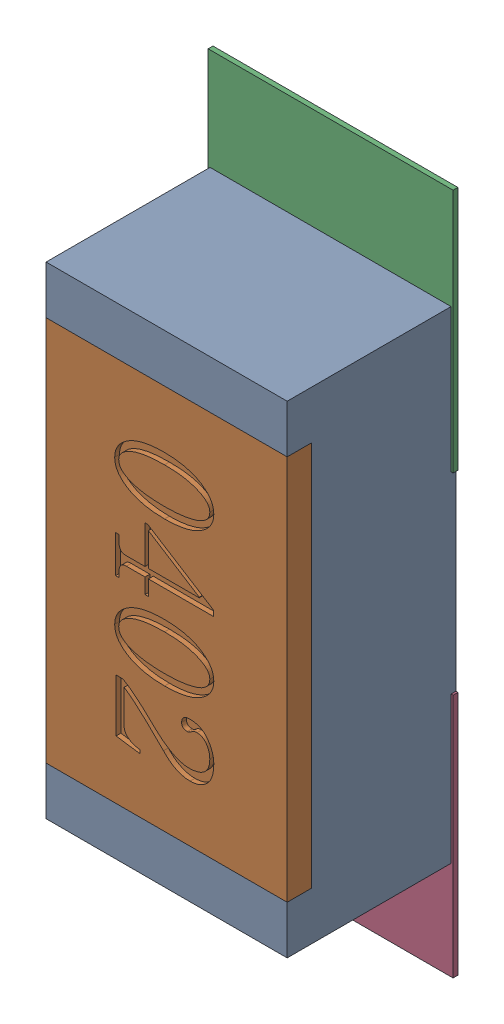
SolidWorks assembly R20, configuration Défaut. Lengths in mm.
Overall size (0.51 1.42 0.35).
5 component instances, 2 part files, 0 mates.
Components (placement in the parent):
- R0402-1: R0402 [Défaut] at (32.5373 -8.4908 0) x (0 -1 0) z (0 0 1) size (1 0.5 0.35)
- 6504207776-1: 6504207776 [Défaut] at (32.5374 -8.0337 0) size (0.51 0.51 0.01)
  - Extruded-1: Extruded [Défaut] at origin size (0.51 0.51 0.01)
- 6504207776-2: 6504207776 [Défaut] at (32.5374 -8.9408 0) size (0.51 0.51 0.01)
  - Extruded-1: Extruded [Défaut] at origin size (0.51 0.51 0.01)
